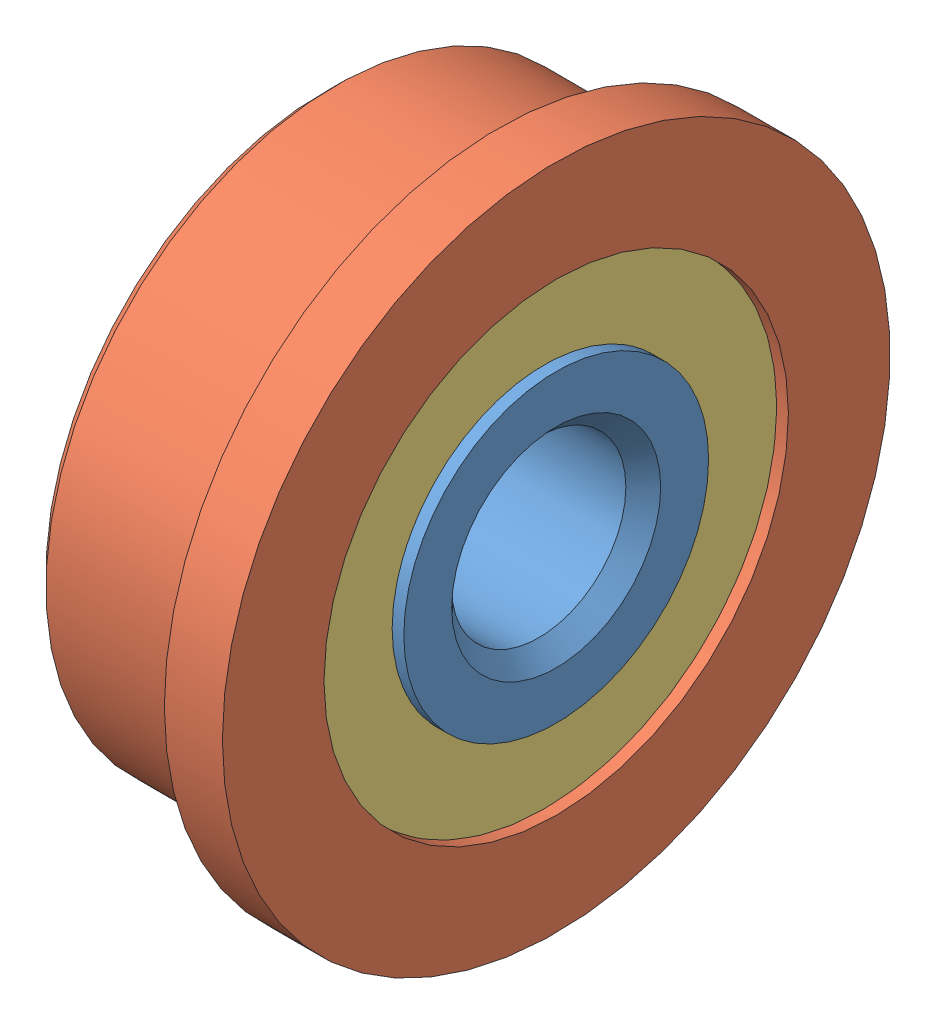
SolidWorks assembly F623ZZ, configuration Default. Lengths in mm.
Overall size (4 11.5 11.5).
11 component instances, 4 part files, 0 mates.
Components (placement in the parent):
- Copy of _F623ZZ Inner ring^F623ZZ-1: Copy of _F623ZZ Inner ring^F623ZZ [Default] at origin size (4 5.25 5.25) (virtual)
- Copy of _F623ZZ Outer ring^F623ZZ-1: Copy of _F623ZZ Outer ring^F623ZZ [Default] at origin size (4 11.5 11.5) (virtual)
- Copy of _F623ZZ Shield^F623ZZ-1: Copy of _F623ZZ Shield^F623ZZ [Default] at origin size (0.1 8 8) (virtual)
- Copy of _F623ZZ Ball^F623ZZ-1: Copy of _F623ZZ Ball^F623ZZ [Default] at (2 3.175 0) x (-1 0 0) z (0 0 1) size (1.59 1.59 1.59) (virtual)
- Copy of _F623ZZ Ball^F623ZZ-2: Copy of _F623ZZ Ball^F623ZZ [Default] at (2 1.9796 2.4823) x (-1 0 0) z (0 0 1) size (1.59 1.59 1.59) (virtual)
- Copy of _F623ZZ Ball^F623ZZ-3: Copy of _F623ZZ Ball^F623ZZ [Default] at (2 -0.7065 3.0954) x (-1 0 0) z (0 0 1) size (1.59 1.59 1.59) (virtual)
- Copy of _F623ZZ Ball^F623ZZ-4: Copy of _F623ZZ Ball^F623ZZ [Default] at (2 -2.8606 1.3776) x (-1 0 0) z (0 0 1) size (1.59 1.59 1.59) (virtual)
- Copy of _F623ZZ Ball^F623ZZ-5: Copy of _F623ZZ Ball^F623ZZ [Default] at (2 -2.8606 -1.3776) x (-1 0 0) z (0 0 1) size (1.59 1.59 1.59) (virtual)
- Copy of _F623ZZ Ball^F623ZZ-6: Copy of _F623ZZ Ball^F623ZZ [Default] at (2 -0.7065 -3.0954) x (-1 0 0) z (0 0 1) size (1.59 1.59 1.59) (virtual)
- Copy of _F623ZZ Ball^F623ZZ-7: Copy of _F623ZZ Ball^F623ZZ [Default] at (2 1.9796 -2.4823) x (-1 0 0) z (0 0 1) size (1.59 1.59 1.59) (virtual)
- Copy of _F623ZZ Shield^F623ZZ-2: Copy of _F623ZZ Shield^F623ZZ [Default] at (4 0 0) x (-1 0 0) z (0 0 1) size (0.1 8 8) (virtual)
